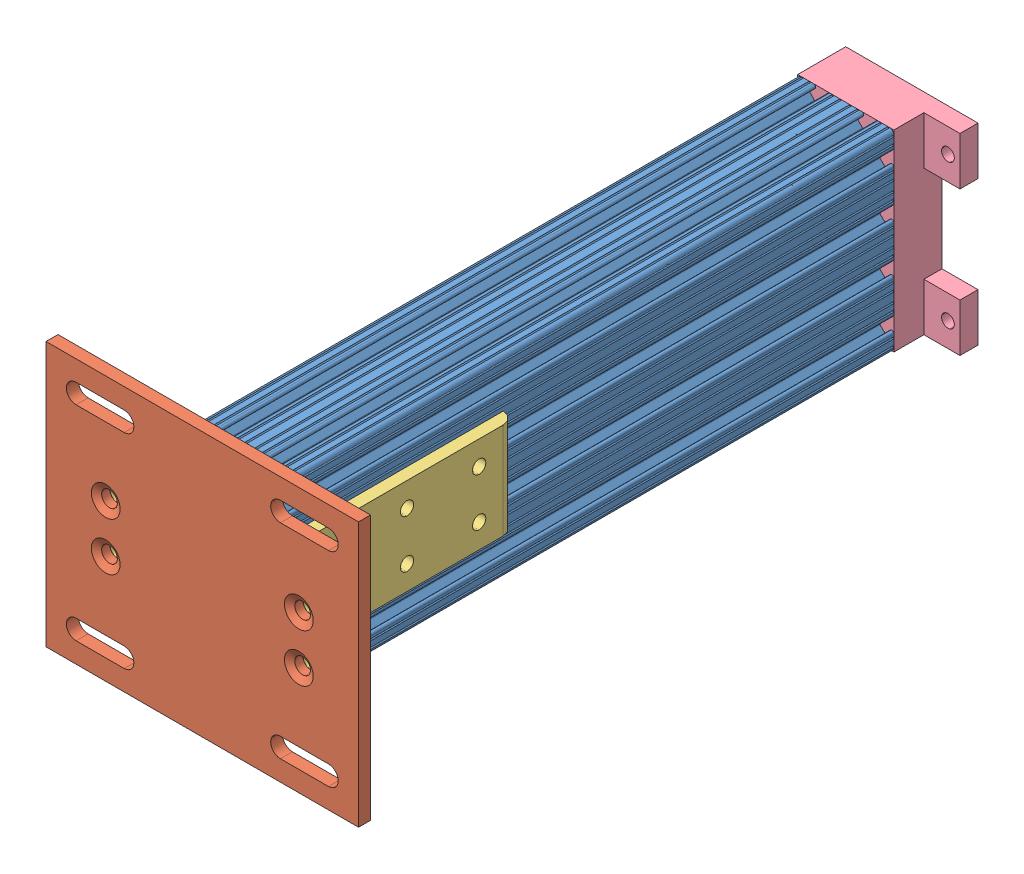
SolidWorks assembly front support leg assembly, configuration Default. Lengths in mm.
Overall size (165.1 139.7 365.13).
6 component instances, 4 part files, 6 mates.
Components (placement in the parent):
- 8020-2040 leg, 13.125in-1: 8020-2040 leg, 13.125in [Default] at (-48.9055 -77.0614 78.1612) size (50.8 101.6 333.38)
- 8020-2387-DEFAULT-1: 8020-2387-DEFAULT [Default] at (-34.9863 -22.6888 91.8816) x (0 1 0) z (-1 0 0) size (139.7 133.35 165.1)
  - 8020-2387-DEFAULT_238708-1: 8020-2387-DEFAULT_238708 [Default] at (-67.1549 7.3704 27.8119) size (139.7 6.35 165.1)
  - 8020-2387-DEFAULT_238509-1: 8020-2387-DEFAULT_238509 [Default] at (9.1264 0.0214 49.7635) x (0 0 1) z (-1 0 0) size (50.8 127 50.8)
  - 8020-2387-DEFAULT_238509-2: 8020-2387-DEFAULT_238509 [Default] at (-41.6736 0.0214 -46.9187) x (0 0 -1) z (1 0 0) size (50.8 127 50.8)
- support leg top bracket-1: support leg top bracket [Default] at (-61.6055 -89.7614 -255.2138) x (0 1 0) z (-1 0 0) size (101.6 25.4 69.85)
Mates (geometry in assembly coordinates):
- Coincident1: coincident anti-aligned: plane of 8020-2040 leg, 13.125in-1 through (-61.6055 -36.3198 78.1612) normal (0 0 1); plane of 8020-2387-DEFAULT-1/8020-2387-DEFAULT_238708-1 through (-36.4088 -207.3239 78.1612) normal (0 0 -1)
- Coincident2: coincident anti-aligned: plane of 8020-2040 leg, 13.125in-1 through (-10.8056 -41.095 -255.2138) normal (1 0 0); plane of 8020-2387-DEFAULT-1/8020-2387-DEFAULT_238509-2 through (-10.8056 -13.5624 150.9329) normal (-1 0 0)
- Distance1: distance = 19.05 mm aligned: plane of 8020-2387-DEFAULT-1/8020-2387-DEFAULT_238708-1 through (-36.4088 -108.8114 78.1612) normal (0 -1 0); plane of 8020-2040 leg, 13.125in-1 through (-38.3391 -89.7614 -255.2138) normal (0 -1 0)
- Coincident3: coincident anti-aligned: plane of 8020-2040 leg, 13.125in-1 through (-61.6055 -36.3198 -255.2138) normal (0 0 -1); plane of support leg top bracket-1 through (-10.8055 -89.7614 -255.2138) normal (0 0 1)
- Concentric1: concentric anti-aligned: circle of 8020-2040 leg, 13.125in-1; circle of support leg top bracket-1
- Concentric2: concentric anti-aligned: circle of 8020-2040 leg, 13.125in-1; circle of support leg top bracket-1
